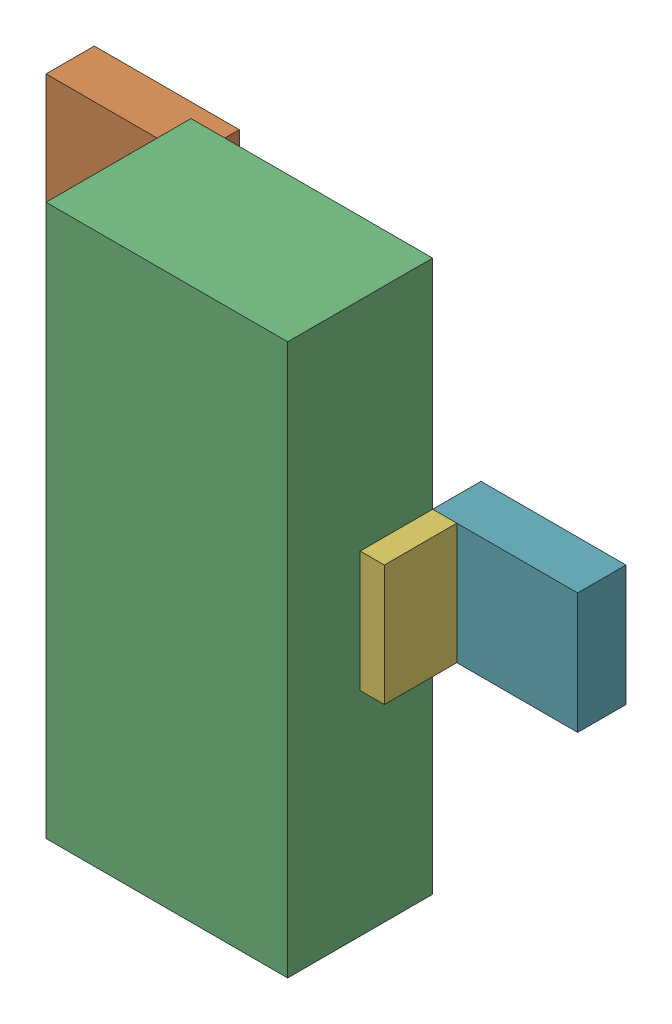
SolidWorks assembly Q3, configuration Default. Lengths in mm.
Overall size (2.79 2.9 1.02).
14 component instances, 3 part files, 0 mates.
Components (placement in the parent):
- 898052496-1: 898052496 [Default] at (32.2834 16.3393 0) size (0.76 0.64 0.25)
  - Extruded_10-1: Extruded_10 [Default] at origin size (0.76 0.64 0.25)
- 898052496-2: 898052496 [Default] at (32.2834 18.2443 0) size (0.76 0.64 0.25)
  - Extruded_10-1: Extruded_10 [Default] at origin size (0.76 0.64 0.25)
- 898052360-1: 898052360 [Default] at (33.2994 17.2918 0.254) size (1.27 2.9 0.76)
  - Extruded_11-1: Extruded_11 [Default] at origin size (1.27 2.9 0.76)
- 898052632-1: 898052632 [Default] at (32.6009 16.3393 0.254) size (0.13 0.64 0.38)
  - Extruded_12-1: Extruded_12 [Default] at origin size (0.13 0.64 0.38)
- 898052632-2: 898052632 [Default] at (32.6009 18.2443 0.254) size (0.13 0.64 0.38)
  - Extruded_12-1: Extruded_12 [Default] at origin size (0.13 0.64 0.38)
- 898052632-3: 898052632 [Default] at (33.9979 17.2791 0.254) size (0.13 0.64 0.38)
  - Extruded_12-1: Extruded_12 [Default] at origin size (0.13 0.64 0.38)
- 898052496-3: 898052496 [Default] at (34.3154 17.2791 0) size (0.76 0.64 0.25)
  - Extruded_10-1: Extruded_10 [Default] at origin size (0.76 0.64 0.25)
